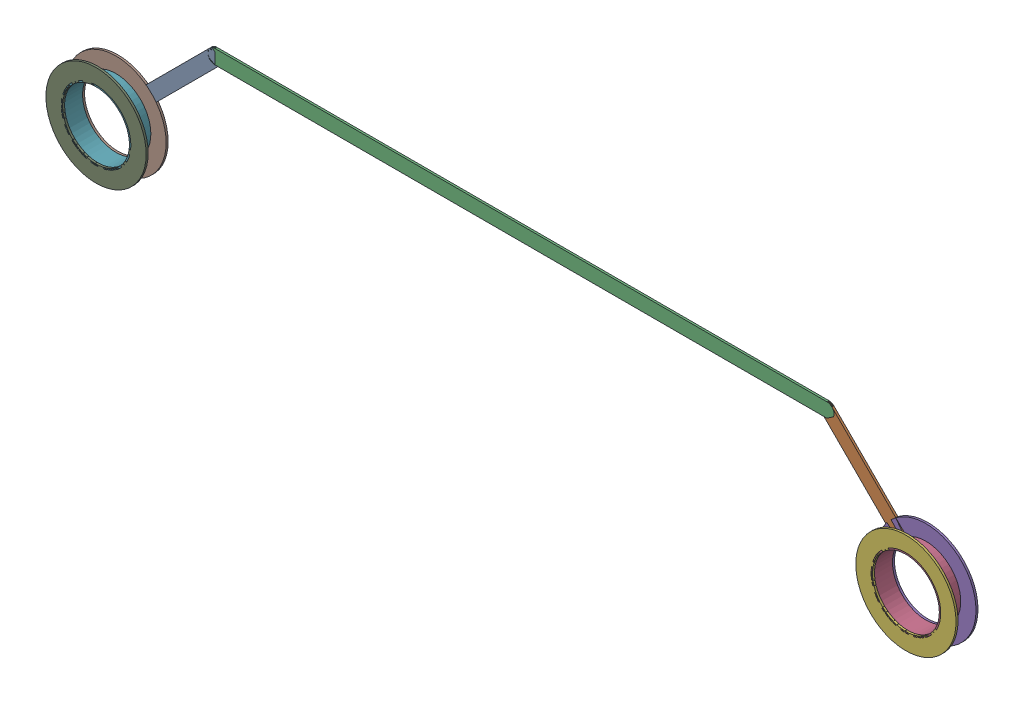
SolidWorks assembly NetU1_1, configuration Predeterminado. Lengths in mm.
Overall size (16.21 2.78 0.39).
23 component instances, 5 part files, 0 mates.
Components (placement in the parent):
- Track (13.758mm,59.438mm)(15.521mm,61.2mm) on Bottom Layer-1: Track (13.758mm,59.438mm)(15.521mm,61.2mm) on Bottom Layer [Predeterminado] at origin size (1.57 1.57 0.04)
  - Track (13.758mm,59.438mm)(15.521mm,61.2mm) on Bottom Layer-1-1: Track (13.758mm,59.438mm)(15.521mm,61.2mm) on Bottom Layer-1 [Predeterminado] at (-68.317 -44.187 -0.4013) size (1.57 1.57 0.04)
    - Track (13.758mm,59.438mm)(15.521mm,61.2mm) on Bottom Layer-Part-1-1: Track (13.758mm,59.438mm)(15.521mm,61.2mm) on Bottom Layer-Part-1 [Predeterminado] at origin size (1.57 1.57 0.04)
- Track (26.416mm,61.2mm)(28.178mm,59.438mm) on Bottom Layer-1: Track (26.416mm,61.2mm)(28.178mm,59.438mm) on Bottom Layer [Predeterminado] at origin size (1.57 1.57 0.04)
  - Track (26.416mm,61.2mm)(28.178mm,59.438mm) on Bottom Layer-1-1: Track (26.416mm,61.2mm)(28.178mm,59.438mm) on Bottom Layer-1 [Predeterminado] at (-68.317 -44.187 -0.4013) size (1.57 1.57 0.04)
    - Track (26.416mm,61.2mm)(28.178mm,59.438mm) on Bottom Layer-Part-1-1: Track (26.416mm,61.2mm)(28.178mm,59.438mm) on Bottom Layer-Part-1 [Predeterminado] at origin size (1.57 1.57 0.04)
- Track (15.521mm,61.2mm)(26.416mm,61.2mm) on Bottom Layer-1: Track (15.521mm,61.2mm)(26.416mm,61.2mm) on Bottom Layer [Predeterminado] at origin size (11.15 0.25 0.04)
  - Track (15.521mm,61.2mm)(26.416mm,61.2mm) on Bottom Layer-1-1: Track (15.521mm,61.2mm)(26.416mm,61.2mm) on Bottom Layer-1 [Predeterminado] at (-68.317 -44.187 -0.4013) size (11.15 0.25 0.04)
    - Track (15.521mm,61.2mm)(26.416mm,61.2mm) on Bottom Layer-Part-1-1: Track (15.521mm,61.2mm)(26.416mm,61.2mm) on Bottom Layer-Part-1 [Predeterminado] at origin size (11.15 0.25 0.04)
- Pad U1-2(28.178mm,59.438mm) on Multi-Layer-1: Pad U1-2(28.178mm,59.438mm) on Multi-Layer [Predeterminado] at origin size (1.79 1.79 0.39)
  - Pad Hole-1: Pad Hole [Predeterminado] at (28.1784 59.4378 -0.4013) size (1.24 1.24 0.39)
    - Pad Hole-Part-1-1: Pad Hole-Part-1 [Predeterminado] at origin size (1.24 1.24 0.39)
  - Top Layer-1: Top Layer [Predeterminado] at (28.1784 59.4378 -0.4013) size (1.79 1.79 0.04)
    - Top Layer-Part-1-1: Top Layer-Part-1 [Predeterminado] at origin size (1.79 1.79 0.04)
  - Top Layer-2: Top Layer [Predeterminado] at (28.1784 59.4378 -0.0457) size (1.79 1.79 0.04)
    - Top Layer-Part-1-1: Top Layer-Part-1 [Predeterminado] at origin size (1.79 1.79 0.04)
- Pad U1-1(13.758mm,59.438mm) on Multi-Layer-1: Pad U1-1(13.758mm,59.438mm) on Multi-Layer [Predeterminado] at origin size (1.79 1.79 0.39)
  - Pad Hole-1: Pad Hole [Predeterminado] at (13.7584 59.4378 -0.4013) size (1.24 1.24 0.39)
    - Pad Hole-Part-1-1: Pad Hole-Part-1 [Predeterminado] at origin size (1.24 1.24 0.39)
  - Top Layer-1: Top Layer [Predeterminado] at (13.7584 59.4378 -0.4013) size (1.79 1.79 0.04)
    - Top Layer-Part-1-1: Top Layer-Part-1 [Predeterminado] at origin size (1.79 1.79 0.04)
  - Top Layer-2: Top Layer [Predeterminado] at (13.7584 59.4378 -0.0457) size (1.79 1.79 0.04)
    - Top Layer-Part-1-1: Top Layer-Part-1 [Predeterminado] at origin size (1.79 1.79 0.04)
